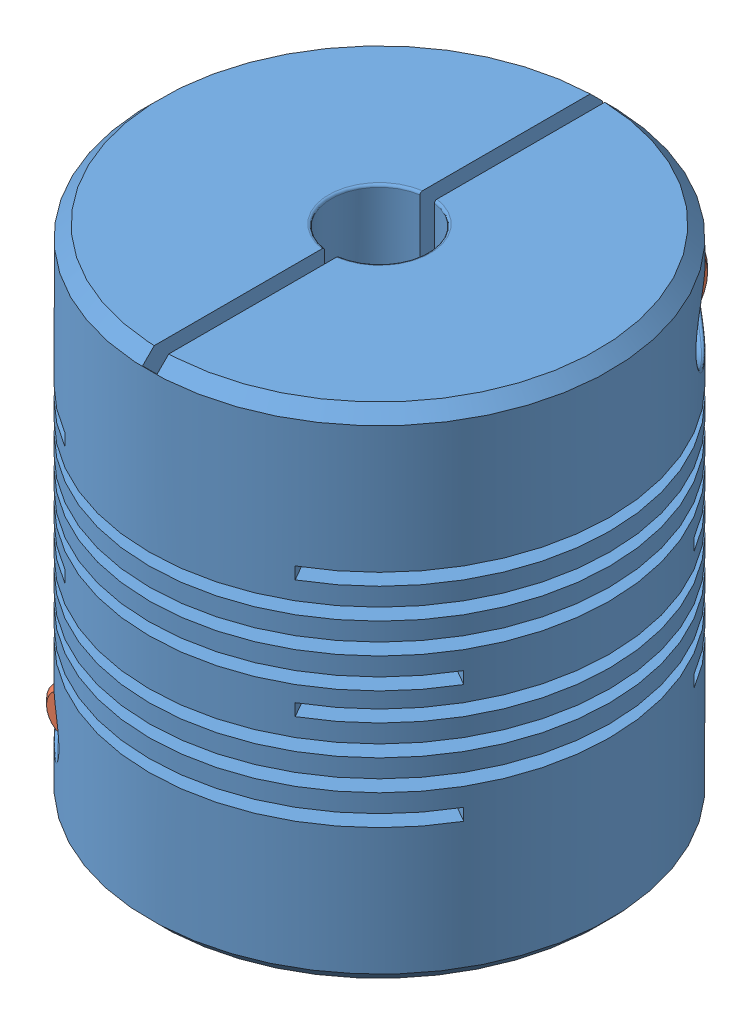
SolidWorks assembly Flexible Coupling MKS-C-2-C-150-08-10, configuration Default. Lengths in mm.
Overall size (38.1 41.32 38.1).
3 component instances, 2 part files, 4 mates.
Components (placement in the parent):
- MKS-C-2-C-150-08-10-1-1: MKS-C-2-C-150-08-10-1 [Default] at (-7.3634 16.4351 -7.2802) size (38.1 41.32 38.1)
- socket head cap screw_am2-3: socket head cap screw_am2 [B18.3.1M - 4 x 0.7 x 20 Hex SHCS -- 20NHX] at (3.6866 10.4351 -20.2802) x (-1 0 0) z (0 0.924225 0.381849) size (24 7 7)
- socket head cap screw_am2-4: socket head cap screw_am2 [B18.3.1M - 4 x 0.7 x 20 Hex SHCS -- 20NHX] at (-20.3634 -18.8649 -18.3302) x (0 0 1) z (-1 0 0) size (24 7 7)
Mates (geometry in assembly coordinates):
- Concentric1: concentric aligned: cylinder of MKS-C-2-C-150-08-10-1-1 through (-0.3134 10.4351 -20.2802) axis (1 0 0) radius 3; cylinder of socket head cap screw_am2-3 through (35.4366 10.4351 -20.2802) axis (1 0 0) radius 2
- Coincident1: coincident anti-aligned: plane of MKS-C-2-C-150-08-10-1-1 through (-0.3134 10.4351 -20.2802) normal (1 0 0); plane of socket head cap screw_am2-3 through (-0.3134 9.0987 -17.0454) normal (-1 0 0)
- Concentric2: concentric anti-aligned: cylinder of MKS-C-2-C-150-08-10-1-1 through (-20.3634 -18.8649 -26.3312) axis (0 0 1) radius 2; cylinder of socket head cap screw_am2-4 through (-20.3634 -18.8649 -50.0802) axis (0 0 -1) radius 3.5
- Coincident2: coincident anti-aligned: plane of MKS-C-2-C-150-08-10-1-1 through (-20.3634 -18.8649 -14.3302) normal (0 0 -1); plane of socket head cap screw_am2-4 through (-20.3634 -15.3649 -14.3302) normal (0 0 1)
